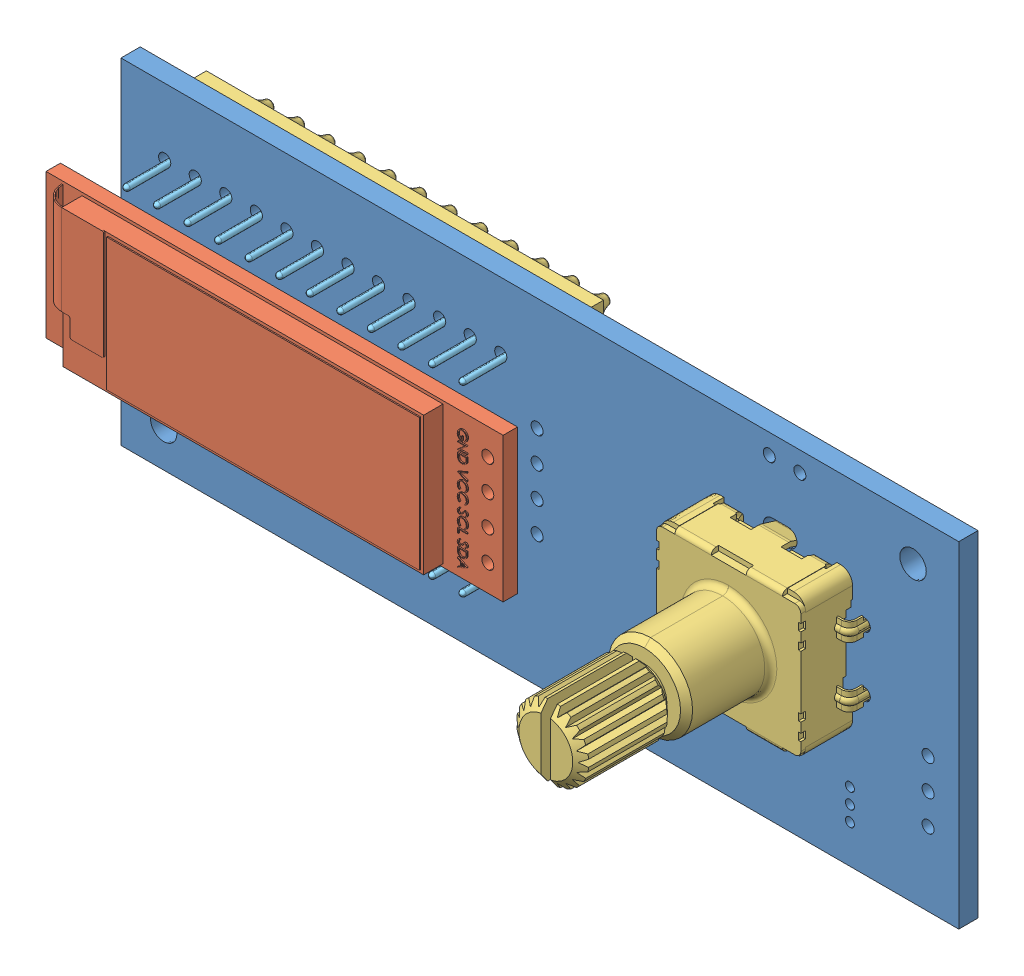
SolidWorks assembly Assem4, configuration Default. Lengths in mm.
Overall size (71.78 27.9 29.29).
62 component instances, 21 part files, 6 mates.
Components (placement in the parent):
- CameraIntervalometer.step-1: CameraIntervalometer.step [Default] at (-116.9591 121.2017 48.7284) size (69.65 27.9 1.6)
  - _autosave-CameraIntervalometer PCB.step-1: _autosave-CameraIntervalometer PCB.step [Default] at origin size (69.65 27.9 1.6)
- 128x32-OLED-1: 128x32-OLED [Default] at (13.1078 38.9667 53.2284) x (-1 0 0) z (0 0 1) size (38 12 2.96)
- ARDUINO PRO MICRO.IGS-1: ARDUINO PRO MICRO.IGS [Default] at (0.0509 46.4031 44.8284) x (1 0 0) z (0 1 0) size (34.6 13.31 17.79)
  - micro board.IGS-1: micro board.IGS [Default] at origin size (33.03 3.11 17.79)
  - MICRO_stackable header 12.IGS-1: MICRO_stackable header 12.IGS [Default] at (0 -3.9 0) size (30.49 2.91 2.55)
  - MICRO_stackable header 12.IGS-2: MICRO_stackable header 12.IGS [Default] at (0 -3.9 -15.24) size (30.49 2.91 2.55)
  - MICRO_stackable header pin.IGS-1: MICRO_stackable header pin.IGS [Default] x (0.999996 0 0.00266) z (-0.00266 0 0.999996) size (1.71 11.9 1.71)
  - MICRO_stackable header pin.IGS-2: MICRO_stackable header pin.IGS [Default] at (2.54 0 0) x (0.999996 0 0.00266) z (-0.00266 0 0.999996) size (1.71 11.9 1.71)
  - MICRO_stackable header pin.IGS-3: MICRO_stackable header pin.IGS [Default] at (5.08 0 0) x (0.999996 0 0.00266) z (-0.00266 0 0.999996) size (1.71 11.9 1.71)
  - MICRO_stackable header pin.IGS-4: MICRO_stackable header pin.IGS [Default] at (7.62 0 0) x (0.999996 0 0.00266) z (-0.00266 0 0.999996) size (1.71 11.9 1.71)
  - MICRO_stackable header pin.IGS-5: MICRO_stackable header pin.IGS [Default] at (10.16 0 0) x (0.999996 0 0.00266) z (-0.00266 0 0.999996) size (1.71 11.9 1.71)
  - MICRO_stackable header pin.IGS-6: MICRO_stackable header pin.IGS [Default] at (12.7 0 0) x (0.999996 0 0.00266) z (-0.00266 0 0.999996) size (1.71 11.9 1.71)
  - MICRO_stackable header pin.IGS-7: MICRO_stackable header pin.IGS [Default] at (15.24 0 0) x (0.999996 0 0.00266) z (-0.00266 0 0.999996) size (1.71 11.9 1.71)
  - MICRO_stackable header pin.IGS-8: MICRO_stackable header pin.IGS [Default] at (17.78 0 0) x (0.999996 0 0.00266) z (-0.00266 0 0.999996) size (1.71 11.9 1.71)
  - MICRO_stackable header pin.IGS-9: MICRO_stackable header pin.IGS [Default] at (20.32 0 0) x (0.999996 0 0.00266) z (-0.00266 0 0.999996) size (1.71 11.9 1.71)
  - MICRO_stackable header pin.IGS-10: MICRO_stackable header pin.IGS [Default] at (22.86 0 0) x (0.999996 0 0.00266) z (-0.00266 0 0.999996) size (1.71 11.9 1.71)
  - MICRO_stackable header pin.IGS-11: MICRO_stackable header pin.IGS [Default] at (25.4 0 0) x (0.999996 0 0.00266) z (-0.00266 0 0.999996) size (1.71 11.9 1.71)
  - MICRO_stackable header pin.IGS-12: MICRO_stackable header pin.IGS [Default] at (27.94 0 0) x (0.999996 0 0.00266) z (-0.00266 0 0.999996) size (1.71 11.9 1.71)
  - MICRO_stackable header pin.IGS-13: MICRO_stackable header pin.IGS [Default] at (0 0 -15.24) x (0.999996 0 0.00266) z (-0.00266 0 0.999996) size (1.71 11.9 1.71)
  - MICRO_stackable header pin.IGS-14: MICRO_stackable header pin.IGS [Default] at (2.54 0 -15.24) x (0.999996 0 0.00266) z (-0.00266 0 0.999996) size (1.71 11.9 1.71)
  - MICRO_stackable header pin.IGS-15: MICRO_stackable header pin.IGS [Default] at (5.08 0 -15.24) x (0.999996 0 0.00266) z (-0.00266 0 0.999996) size (1.71 11.9 1.71)
  - MICRO_stackable header pin.IGS-16: MICRO_stackable header pin.IGS [Default] at (7.62 0 -15.24) x (0.999996 0 0.00266) z (-0.00266 0 0.999996) size (1.71 11.9 1.71)
  - MICRO_stackable header pin.IGS-17: MICRO_stackable header pin.IGS [Default] at (10.16 0 -15.24) x (0.999996 0 0.00266) z (-0.00266 0 0.999996) size (1.71 11.9 1.71)
  - MICRO_stackable header pin.IGS-18: MICRO_stackable header pin.IGS [Default] at (12.7 0 -15.24) x (0.999996 0 0.00266) z (-0.00266 0 0.999996) size (1.71 11.9 1.71)
  - MICRO_stackable header pin.IGS-19: MICRO_stackable header pin.IGS [Default] at (15.24 0 -15.24) x (0.999996 0 0.00266) z (-0.00266 0 0.999996) size (1.71 11.9 1.71)
  - MICRO_stackable header pin.IGS-20: MICRO_stackable header pin.IGS [Default] at (17.78 0 -15.24) x (0.999996 0 0.00266) z (-0.00266 0 0.999996) size (1.71 11.9 1.71)
  - MICRO_stackable header pin.IGS-21: MICRO_stackable header pin.IGS [Default] at (20.32 0 -15.24) x (0.999996 0 0.00266) z (-0.00266 0 0.999996) size (1.71 11.9 1.71)
  - MICRO_stackable header pin.IGS-22: MICRO_stackable header pin.IGS [Default] at (22.86 0 -15.24) x (0.999996 0 0.00266) z (-0.00266 0 0.999996) size (1.71 11.9 1.71)
  - MICRO_stackable header pin.IGS-23: MICRO_stackable header pin.IGS [Default] at (25.4 0 -15.24) x (0.999996 0 0.00266) z (-0.00266 0 0.999996) size (1.71 11.9 1.71)
  - MICRO_stackable header pin.IGS-24: MICRO_stackable header pin.IGS [Default] at (27.94 0 -15.24) x (0.999996 0 0.00266) z (-0.00266 0 0.999996) size (1.71 11.9 1.71)
  - micro usb shell.IGS-1: micro usb shell.IGS [Default] at (-4.75 1.85 -7.62) x (0 0 1) z (-1 0 0) size (8.01 2.96 5.64)
  - micro usb internal.IGS-1: micro usb internal.IGS [Default] at (-4.75 1.6 -7.62) x (0 0 1) z (-1 0 0) size (6.91 2.91 4.01)
  - micro usb contact.IGS-1: micro usb contact.IGS [Default] at (-4.65 1.6 -6.32) x (0 0 1) z (-1 0 0) size (0.21 1.31 4.41)
  - micro usb contact.IGS-2: micro usb contact.IGS [Default] at (-4.65 1.6 -6.97) x (0 0 1) z (-1 0 0) size (0.21 1.31 4.41)
  - micro usb contact.IGS-3: micro usb contact.IGS [Default] at (-4.65 1.6 -7.62) x (0 0 1) z (-1 0 0) size (0.21 1.31 4.41)
  - micro usb contact.IGS-4: micro usb contact.IGS [Default] at (-4.65 1.6 -8.27) x (0 0 1) z (-1 0 0) size (0.21 1.31 4.41)
  - micro usb contact.IGS-5: micro usb contact.IGS [Default] at (-4.65 1.6 -8.92) x (0 0 1) z (-1 0 0) size (0.21 1.31 4.41)
  - atmega32U4.IGS-1: atmega32U4.IGS [Default] at (15.24 1.62 -7.62) x (-0.707107 0 0.707107) z (-0.707107 0 -0.707107) size (7.24 1.03 7.24)
  - MICRO_cap106C.IGS-1: MICRO_cap106C.IGS [Default] at (7.3558 1.6 -11.4427) x (0 0 -1) z (1 0 0) size (1.71 1.82 4.04)
  - MICRO_cap106C.IGS-2: MICRO_cap106C.IGS [Default] at (7.3558 1.6 -3.7973) x (0 0 -1) z (1 0 0) size (1.71 1.82 4.04)
  - micro_crystal 5x3.IGS-1: micro_crystal 5x3.IGS [Default] at (27.051 1.65 -7.62) x (0 0 -1) z (1 0 0) size (5.71 1.01 3.41)
  - micro_MIC5219.IGS-1: micro_MIC5219.IGS [Default] at (7.366 1.6 -7.874) x (-1 0 0) z (0 0 -1) size (2.91 1.21 3.7)
  - MICRO_603 resistor 103.IGS-1: MICRO_603 resistor 103.IGS [Default] at (1.27 1.6 -3.81) x (0 0 1) z (-1 0 0) size (2.37 0.62 1.03)
  - MICRO_603 resistor 102.IGS-1: MICRO_603 resistor 102.IGS [Default] at (2.667 1.6 -3.81) x (0 0 1) z (-1 0 0) size (2.37 0.63 1.03)
  - MICRO_603 resistor 22.IGS-1: MICRO_603 resistor 22.IGS [Default] at (1.27 1.6 -11.43) x (0 0 1) z (-1 0 0) size (2.37 0.63 1.03)
  - MICRO_603 resistor 22.IGS-2: MICRO_603 resistor 22.IGS [Default] at (2.667 1.6 -11.43) x (0 0 1) z (-1 0 0) size (2.37 0.63 1.03)
  - MICRO_PTC-1206.IGS-1: MICRO_PTC-1206.IGS [Default] at (4.445 1.6 -7.62) x (0 0 1) z (-1 0 0) size (3.85 1.18 1.83)
  - MICRO_603 resistor 331.IGS-1: MICRO_603 resistor 331.IGS [Default] at (27.432 1.6 -11.938) size (2.37 0.62 1.03)
  - MICRO_603 resistor 331.IGS-2: MICRO_603 resistor 331.IGS [Default] at (27.432 1.6 -3.302) size (2.37 0.62 1.03)
  - MICRO_603 cap on pad.IGS-1: MICRO_603 cap on pad.IGS [Default] at (24.384 1.6 -9.398) x (0 0 1) z (-1 0 0) size (2.77 0.91 1.03)
  - MICRO_603 cap on pad.IGS-2: MICRO_603 cap on pad.IGS [Default] at (21.336 1.6 -11.938) size (2.77 0.91 1.03)
  - MICRO_603 cap on pad.IGS-3: MICRO_603 cap on pad.IGS [Default] at (24.384 1.6 -5.715) x (0 0 1) z (-1 0 0) size (2.77 0.91 1.03)
  - MICRO_603 cap on pad.IGS-4: MICRO_603 cap on pad.IGS [Default] at (21.336 1.6 -3.1877) size (2.77 0.91 1.03)
  - MICRO_603 cap on pad.IGS-5: MICRO_603 cap on pad.IGS [Default] at (11.0744 1.6 -3.5839) x (0 0 -1) z (1 0 0) size (2.77 0.91 1.03)
  - MICRO_603 cap on pad.IGS-6: MICRO_603 cap on pad.IGS [Default] at (10.6528 1.6 -11.4681) x (0 0 1) z (-1 0 0) size (2.77 0.91 1.03)
  - MICRO_603 cap on pad.IGS-7: MICRO_603 cap on pad.IGS [Default] at (4.1758 1.6 -11.43) x (0 0 -1) z (1 0 0) size (2.77 0.91 1.03)
  - SOD 323.IGS-1: SOD 323.IGS [Default] at (2.6416 1.6 -7.62) x (0 0 1) z (-1 0 0) size (2.94 1.12 1.26)
  - MICRO_led.IGS-1: MICRO_led.IGS [Default] at (24.384 1.62 -2.6907) size (2.53 0.73 0.81)
  - MICRO_led.IGS-2: MICRO_led.IGS [Default] at (24.384 1.62 -11.938) size (2.53 0.73 0.81)
  - MICRO_led.IGS-3: MICRO_led.IGS [Default] at (4.1046 1.62 -3.81) x (0 0 -1) z (1 0 0) size (2.53 0.73 0.81)
- EC11 Rotary Encoder Dode Switch-15mm .step-1: EC11 Rotary Encoder Dode Switch-15mm .step [Default] at (51.1018 39.773 50.3653) x (0 -1 0) z (0 0 1) size (11.71 14.96 23.16)
Mates (geometry in assembly coordinates):
- Tangent1: tangent: plane of assembly; plane of CameraIntervalometer.step-1/_autosave-CameraIntervalometer PCB.step-1 through (31.0659 38.2017 48.7284) normal (0 0 -1); face of ARDUINO PRO MICRO.IGS-1/MICRO_stackable header 12.IGS-1
- Tangent5: tangent anti-aligned: plane of CameraIntervalometer.step-1/_autosave-CameraIntervalometer PCB.step-1 through (-3.7591 24.2517 48.7284) normal (-1 0 0); edge_curve of ARDUINO PRO MICRO.IGS-1/micro board.IGS-1
- Concentric1: concentric aligned: cylinder of CameraIntervalometer.step-1/_autosave-CameraIntervalometer PCB.step-1 through (30.8359 42.7767 47.9284) axis (0 0 1) radius 0.5; cylinder of 128x32-OLED-1 through (30.8359 42.7767 44.4284) axis (0 0 1) radius 0.5
- Parallel1: parallel anti-aligned: plane of CameraIntervalometer.step-1/_autosave-CameraIntervalometer PCB.step-1 through (31.0659 38.2017 50.3284) normal (0 0 1); plane of 128x32-OLED-1 through (13.1078 38.9667 53.2284) normal (0 0 -1)
- Concentric2: concentric aligned: circle of CameraIntervalometer.step-1/_autosave-CameraIntervalometer PCB.step-1; circle of 128x32-OLED-1
- Distance1: distance = 2.9 mm anti-aligned: plane of 128x32-OLED-1 through (13.1078 38.9667 53.2284) normal (0 0 -1); plane of CameraIntervalometer.step-1/_autosave-CameraIntervalometer PCB.step-1 through (31.0659 38.2017 50.3284) normal (0 0 1)
